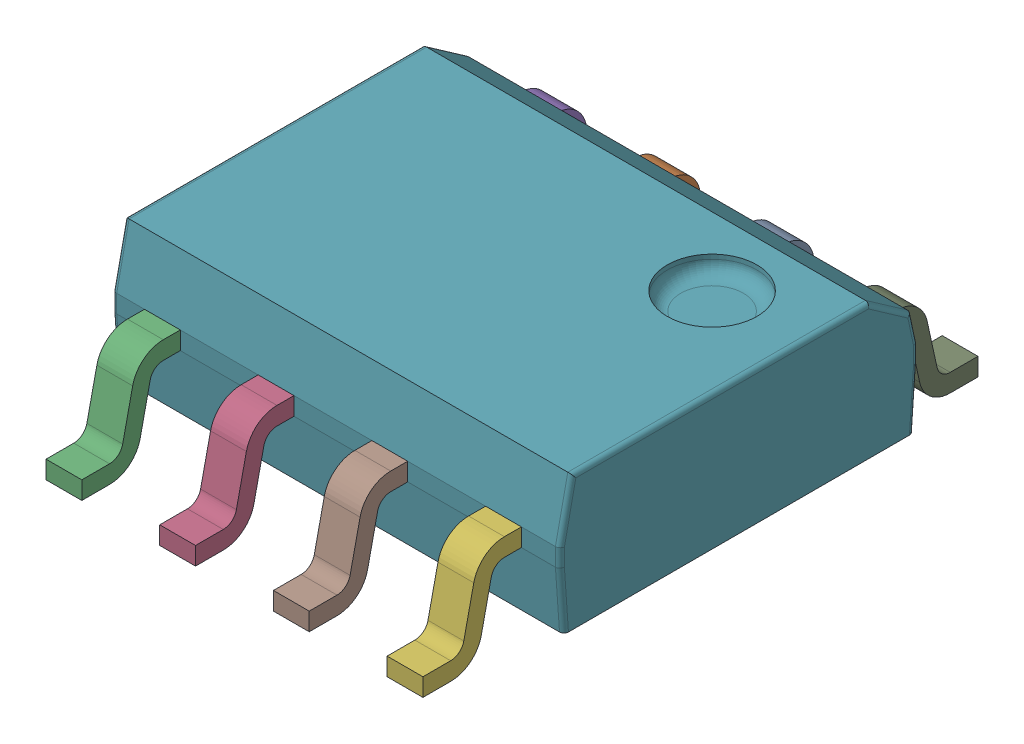
SolidWorks assembly User_Library-SOIC-8-150, configuration Default. Lengths in mm.
Overall size (5 1.75 6.2).
9 component instances, 2 part files, 0 mates.
Components (placement in the parent):
- User_Library-SOIC-8-150_pin_SOIC_SO-150_1_1-1: User_Library-SOIC-8-150_pin_SOIC_SO-150_1_1 [Default] at (0.6 0 -2) x (-1 0 0) z (0 0 -1) size (0.4 1.1 1.1)
- User_Library-SOIC-8-150_pin_SOIC_SO-150_1_1-2: User_Library-SOIC-8-150_pin_SOIC_SO-150_1_1 [Default] at (-0.67 0 -2) x (-1 0 0) z (0 0 -1) size (0.4 1.1 1.1)
- User_Library-SOIC-8-150_pin_SOIC_SO-150_1_1-3: User_Library-SOIC-8-150_pin_SOIC_SO-150_1_1 [Default] at (-1.94 0 2) size (0.4 1.1 1.1)
- User_Library-SOIC-8-150_pin_SOIC_SO-150_1_1-4: User_Library-SOIC-8-150_pin_SOIC_SO-150_1_1 [Default] at (-0.67 0 2) size (0.4 1.1 1.1)
- User_Library-SOIC-8-150_pin_SOIC_SO-150_1_1-5: User_Library-SOIC-8-150_pin_SOIC_SO-150_1_1 [Default] at (-1.94 0 -2) x (-1 0 0) z (0 0 -1) size (0.4 1.1 1.1)
- User_Library-SOIC-8-150_pin_SOIC_SO-150_1_1-6: User_Library-SOIC-8-150_pin_SOIC_SO-150_1_1 [Default] at (1.87 0 2) size (0.4 1.1 1.1)
- User_Library-SOIC-8-150_SOIC_150_SOIC_5X4_1_1-1: User_Library-SOIC-8-150_SOIC_150_SOIC_5X4_1_1 [Default] at origin size (5 1.5 4)
- User_Library-SOIC-8-150_pin_SOIC_SO-150_1_1-7: User_Library-SOIC-8-150_pin_SOIC_SO-150_1_1 [Default] at (0.6 0 2) size (0.4 1.1 1.1)
- User_Library-SOIC-8-150_pin_SOIC_SO-150_1_1-8: User_Library-SOIC-8-150_pin_SOIC_SO-150_1_1 [Default] at (1.87 0 -2) x (-1 0 0) z (0 0 -1) size (0.4 1.1 1.1)
